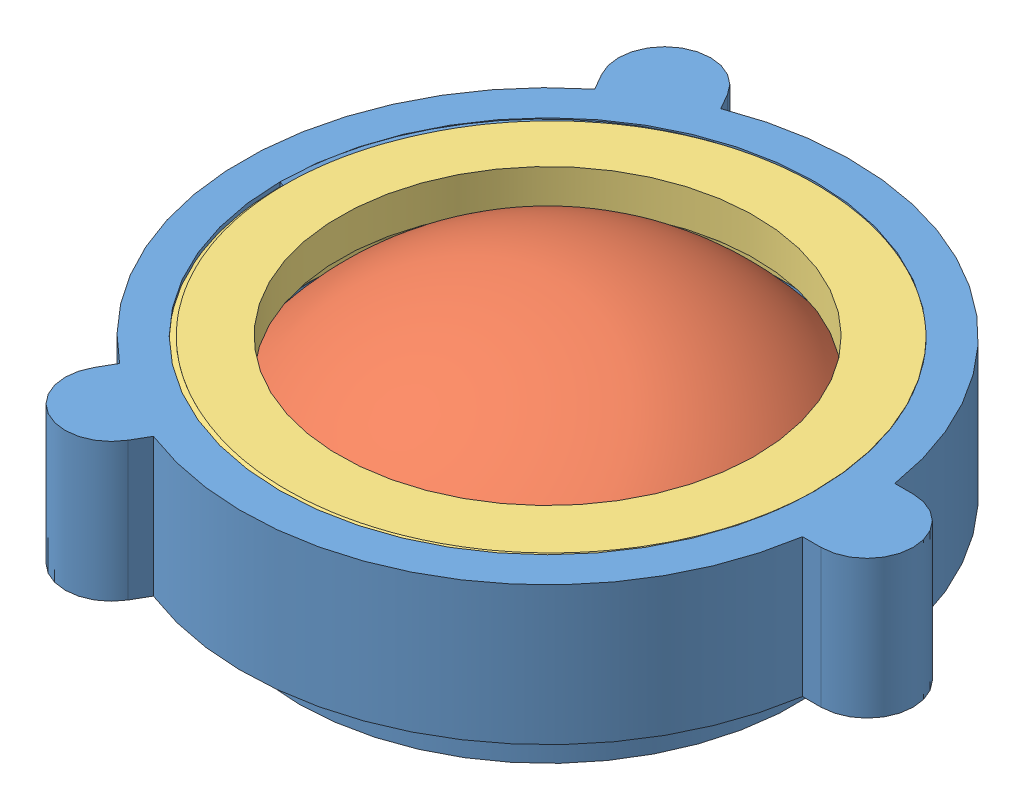
SolidWorks assembly optics-assem, configuration Default. Lengths in mm.
Overall size (75.53 26.29 71.83).
3 component instances, 3 part files, 3 mates.
Components (placement in the parent):
- lens-holder-1: lens-holder [Default] at (0 20 0) size (72.62 21 69.96)
- plano-convex-d50-f60-1: plano-convex-d50-f60 [Default] at (0 28.145 0) x (0.719678 0 0.694308) z (0 1 0) size (50.8 50.8 16.29)
- lens-screw-1: lens-screw [Default] at (0 23.0197 0) x (0.999968 0 0.008041) z (-0.008041 0 0.999968) size (58 8.36 58)
Mates (geometry in assembly coordinates):
- Coincident4: coincident anti-aligned: line of lens-holder-1 through (39.6 0 8.2) axis (0 0 1)
- Coincident6: coincident anti-aligned: line of plano-convex-d50-f60-1 through (0 19.1855 0) axis (0 1 0)
- Coincident8: coincident aligned: line of lens-screw-1 through (11 0 33.5197) axis (0 0 -1)
